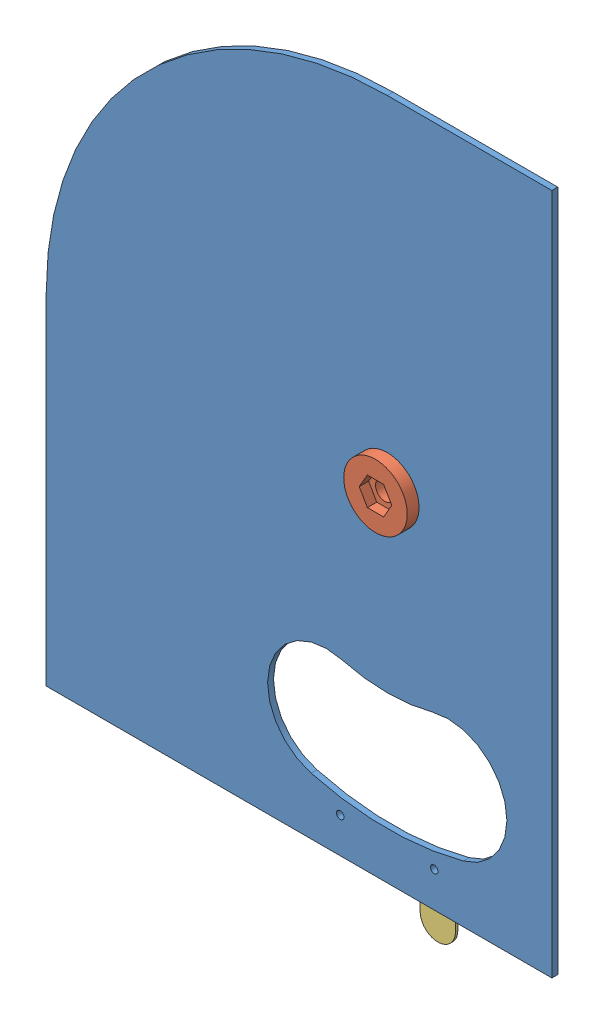
SolidWorks assembly Ferris Assembly, configuration Default. Lengths in mm.
Overall size (215 302.5 8).
19 component instances, 7 part files, 13 mates.
Components (placement in the parent):
- Containment Plate-1: Containment Plate [Insertion - Wide] x (-1 0 0) z (0 -1 0) size (215 2.5 290)
- Wheel Assembly-1: Wheel Assembly [Default] at (0 145 -25) x (-1 0.000748 0) z (0 0 1) size (278.08 278.08 14) (hidden)
  - Ferris Plate-1: Ferris Plate [Default] at (0 0 -7) x (1 0 0) z (0 1 0) size (278.08 1 278.08)
  - Center Spacer-1: Center Spacer [Default] at origin size (46.64 42 12)
  - Perimeter Spacer-1: Perimeter Spacer [Default] at (-36.288 111.683 6) x (0 -1 0) z (0 0 -1) size (12 12 12)
  - Perimeter Spacer-2: Perimeter Spacer [Default] at (-95.0032 69.0239 6) x (0.587785 -0.809017 0) z (0 0 -1) size (12 12 12)
  - Perimeter Spacer-3: Perimeter Spacer [Default] at (-117.4305 0 6) x (0.951057 -0.309017 0) z (0 0 -1) size (12 12 12)
  - Perimeter Spacer-4: Perimeter Spacer [Default] at (-95.0032 -69.0239 6) x (0.951057 0.309017 0) z (0 0 -1) size (12 12 12)
  - Perimeter Spacer-5: Perimeter Spacer [Default] at (-36.288 -111.683 6) x (0.587785 0.809017 0) z (0 0 -1) size (12 12 12)
  - Perimeter Spacer-6: Perimeter Spacer [Default] at (36.288 -111.683 6) x (0 1 0) z (0 0 -1) size (12 12 12)
  - Perimeter Spacer-7: Perimeter Spacer [Default] at (95.0032 -69.0239 6) x (-0.587785 0.809017 0) z (0 0 -1) size (12 12 12)
  - Perimeter Spacer-8: Perimeter Spacer [Default] at (117.4305 0 6) x (-0.951057 0.309017 0) z (0 0 -1) size (12 12 12)
  - Perimeter Spacer-9: Perimeter Spacer [Default] at (95.0032 69.0239 6) x (-0.951057 -0.309017 0) z (0 0 -1) size (12 12 12)
  - Perimeter Spacer-10: Perimeter Spacer [Default] at (36.288 111.683 6) x (-0.587785 -0.809017 0) z (0 0 -1) size (12 12 12)
  - Ferris Plate-2: Ferris Plate [Toothless] at (0 0 7) x (-1 0 0) z (0 1 0) size (270 1 270)
- Containment Plate-2: Containment Plate [Ejection Side] at (0 0 -47.5) x (-1 0 0) z (0 -1 0) size (215 2.5 290) (hidden)
- Axle Bolt Head Holder-1: Axle Bolt Head Holder [Default] at (0 145 -3) size (27 27 8)
- Axle Bolt Nut Holder-1: Axle Bolt Nut Holder [Default] at (0 145 -47) x (-1 0 0) z (0 0 -1) size (27 27 8) (hidden)
- Insertion Ramp-1: Insertion Ramp [Default] at (0 0 -2.5) x (-1 0 0) z (0 0 -1) size (15 12.5 1)
Mates (geometry in assembly coordinates):
- Coincident1: coincident anti-aligned: plane of Containment Plate-1; plane of assembly through (0 0 0) normal (0 0 1)
- Coincident2: coincident anti-aligned: plane of Containment Plate-1; plane of assembly through (0 0 0) normal (1 0 0)
- Coincident3: coincident anti-aligned: plane of Containment Plate-1 through (0 0 0) normal (0 -1 0); plane of assembly through (0 0 0) normal (0 1 0)
- Parallel1: parallel aligned: plane of Containment Plate-1 through (0 145 -2.5) normal (0 0 -1); plane of Containment Plate-2 through (0 145 -50) normal (0 0 -1)
- Coincident5: coincident aligned: plane of Containment Plate-1 through (0 0 0) normal (0 -1 0); plane of Containment Plate-2 through (0 0 -47.5) normal (0 -1 0)
- Coincident6: coincident aligned: plane of Containment Plate-1; plane of Containment Plate-2
- Coincident12: coincident anti-aligned: line of Containment Plate-1 through (-5.7735 155 0) axis (1 0 0); line of Axle Bolt Head Holder-1 through (5.7735 155 0) axis (-1 0 0)
- Coincident13: coincident anti-aligned: line of Containment Plate-1 through (-11.547 145 0) axis (0.5 0.866025 0); line of Axle Bolt Head Holder-1 through (-5.7735 155 0) axis (-0.5 -0.866025 0)
- Coincident14: coincident aligned: line of Containment Plate-2 through (-5.7735 155 -50) axis (1 0 0); line of Axle Bolt Nut Holder-1 through (-5.7735 155 -50) axis (1 0 0)
- Coincident17: coincident aligned: line of Containment Plate-2 through (5.7735 155 -50) axis (0.5 -0.866025 0); line of Axle Bolt Nut Holder-1 through (5.7735 155 -50) axis (0.5 -0.866025 0)
- Concentric1: concentric aligned: circle of Wheel Assembly-1/Ferris Plate-2; circle of Axle Bolt Nut Holder-1
- Width1: width anti-aligned: plane of Containment Plate-2 through (0 145 -47.5) normal (0 0 1); plane of Containment Plate-1 through (0 145 -2.5) normal (0 0 -1); plane of Wheel Assembly-1/Ferris Plate-1 through (0 145 -32) normal (0 0 -1); plane of Wheel Assembly-1/Ferris Plate-2 through (0 145 -18) normal (0 0 1)
- Distance1: distance = 45 mm anti-aligned: plane of Containment Plate-2 through (0 145 -47.5) normal (0 0 1); plane of Containment Plate-1 through (0 145 -2.5) normal (0 0 -1)
